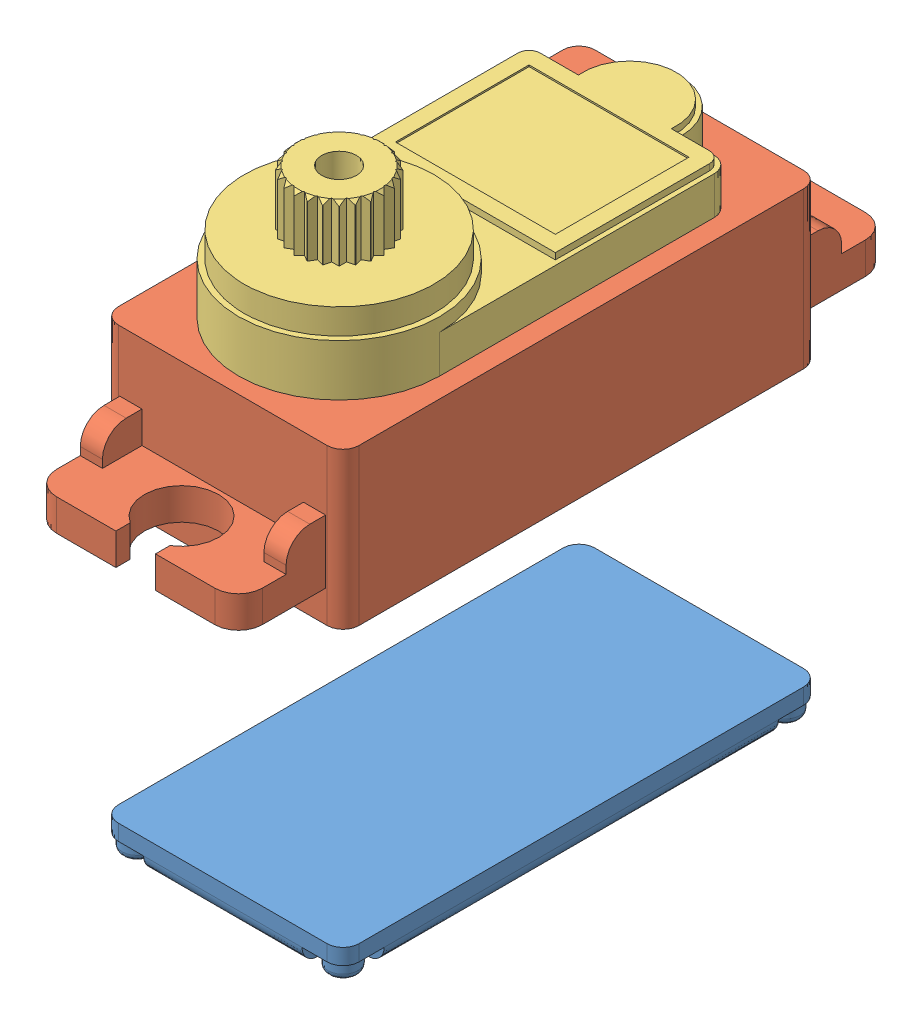
SolidWorks assembly HS-5086WP, configuration Default. Lengths in mm.
Overall size (15.2 37.62 41.1).
4 component instances, 4 part files, 9 mates.
Components (placement in the parent):
- HS-5086WP_bottom-1: HS-5086WP_bottom [Default] at (-14.7907 -7.6082 11.4451) size (15.2 2.02 30.1)
- HS-5086WP_midle-1: HS-5086WP_midle [Default] at (-14.7907 -5.6082 11.4451) (suppressed, hidden)
- HS-5086WP_upper-1: HS-5086WP_upper [Default] at (-14.7907 11.7918 11.4451) size (15.2 9.85 41.1)
- HS-5086WP_top-1: HS-5086WP_top [Default] at (-14.7907 21.6418 10.4451) size (12.7 8.35 27.95)
Mates (geometry in assembly coordinates):
- Coincident1: coincident aligned: line of HS-5086WP_bottom-1 through (-21.3907 -5.6082 26.4951) axis (1 0 0); line of HS-5086WP_midle-1 through (-21.3907 -5.6082 26.4951) axis (1 0 0)
- Coincident2: coincident aligned: line of HS-5086WP_bottom-1 through (-7.1907 -5.6082 25.4951) axis (0 0 -1); line of HS-5086WP_midle-1 through (-7.1907 -5.6082 25.4951) axis (0 0 -1)
- Coincident3: coincident aligned: plane of HS-5086WP_upper-1 through (-7.1907 21.6418 26.4951) normal (0 0 1); plane of HS-5086WP_midle-1 through (-7.1907 11.7918 26.4951) normal (0 0 1)
- Coincident4: coincident aligned: line of HS-5086WP_midle-1 through (-7.1907 11.7918 25.4951) axis (0 0 -1); line of HS-5086WP_upper-1 through (-7.1907 11.7918 25.4951) axis (0 0 -1)
- Coincident6: coincident aligned: plane of HS-5086WP_midle-1 through (-22.3907 11.7918 26.4951) normal (-1 0 0); plane of HS-5086WP_upper-1 through (-22.3907 21.6418 26.4951) normal (-1 0 0)
- Coincident7: coincident anti-aligned: plane of HS-5086WP_upper-1 through (-22.3907 21.6418 -3.6049) normal (0 1 0); plane of HS-5086WP_top-1 through (-40.3431 21.6418 10.4451) normal (0 -1 0)
- Parallel1: parallel aligned: plane of HS-5086WP_upper-1 through (-22.3907 21.6418 26.4951) normal (-1 0 0); plane of HS-5086WP_top-1 through (-21.1407 24.0418 10.4451) normal (-1 0 0)
- Distance2: distance = 1 mm: point of HS-5086WP_upper-1; unknown of HS-5086WP_top-1
- Distance3: distance = 1.25 mm aligned: plane of HS-5086WP_upper-1 through (-22.3907 21.6418 26.4951) normal (-1 0 0); plane of HS-5086WP_top-1 through (-21.1407 24.0418 10.4451) normal (-1 0 0)
